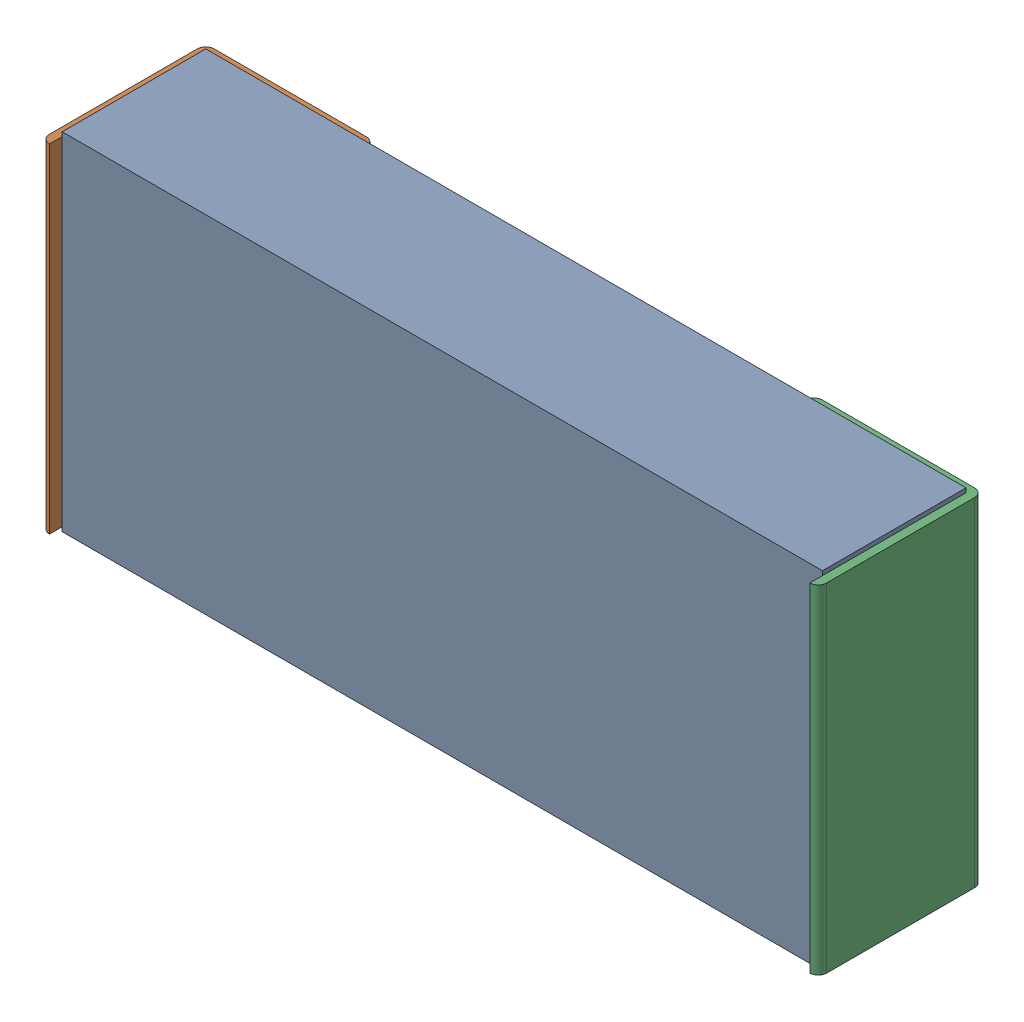
SolidWorks assembly C3, configuration Predeterminado. Lengths in mm.
Overall size (2.34 1.04 0.5).
4 component instances, 3 part files, 0 mates.
Components (placement in the parent):
- Open CASCADE STEP translator 6.8 1.5.1-1: Open CASCADE STEP translator 6.8 1.5.1 [Predeterminado] at origin size (2.34 1.04 0.5)
  - Body_1_2-1: Body_1_2 [Predeterminado] at origin size (2.29 1.04 0.43)
  - Pin_1_2-1: Pin_1_2 [Predeterminado] at (0.3048 0 0) x (-1 0 0) z (0 0 1) size (0.51 1.02 0.5)
  - Pin_2_2-1: Pin_2_2 [Predeterminado] at origin size (0.51 1.02 0.5)
